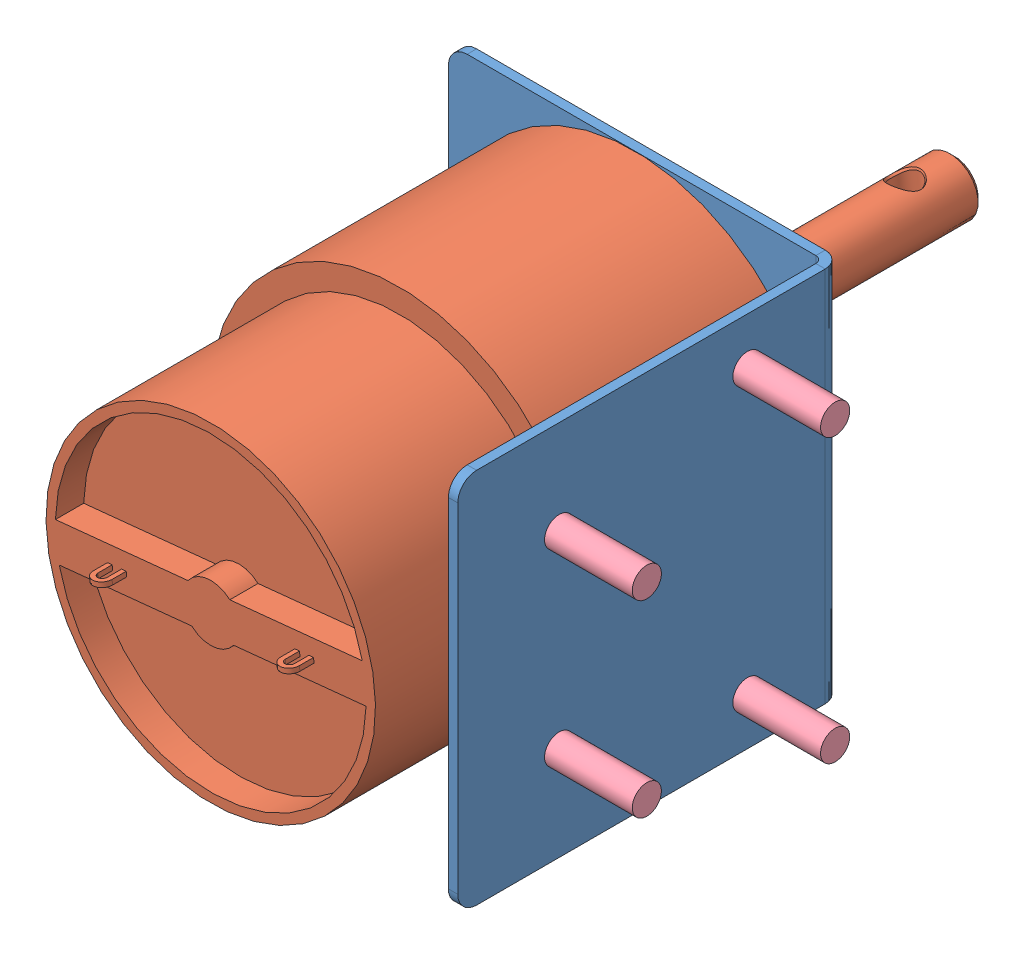
SolidWorks assembly DC motor assembly-12 V , configuration Default. Lengths in mm.
Overall size (52.23 43.84 81.5).
7 component instances, 4 part files, 12 mates.
Components (placement in the parent):
- L-stripe motor holder-1: L-stripe motor holder [Default] at (18.2505 17.963 12.0789) size (40.77 40 40.77)
- Motor for ioe robocon 2018-1: Motor for ioe robocon 2018 [Default] at (-1.9841 17.963 57.0789) x (-0.101002 0.994886 0) z (0 0 -1) size (40 40 81.5)
- Motor-stripe nut-1: Motor-stripe nut [Default] at (-1.9841 17.963 11.0789) x (-0.202187 -0.979347 0) z (0 0 -1) size (20 23.09 5)
- Stripe screw-1: Stripe screw [Default] at (28.3317 32.963 21.0789) x (0 0.680976 -0.732306) z (0 0.732306 0.680976) size (5 10.6 4.9)
- Stripe screw-2: Stripe screw [Default] at (28.3317 2.963 21.0789) x (0 0.97632 -0.216331) z (0 0.216331 0.97632) size (5 10.6 4.9)
- Stripe screw-3: Stripe screw [Default] at (28.3317 7.963 41.0789) x (0 0.554488 -0.832192) z (0 0.832192 0.554488) size (5 10.6 4.9)
- Stripe screw-4: Stripe screw [Default] at (28.3317 27.963 41.0789) x (0 0.554 -0.832517) z (0 0.832517 0.554) size (5 10.6 4.9)
Mates (geometry in assembly coordinates):
- Concentric2: concentric aligned: circle of L-stripe motor holder-1; circle of Motor-stripe nut-1
- Coincident4: coincident anti-aligned: plane of L-stripe motor holder-1 through (18.2505 17.963 11.0789) normal (0 0 -1); plane of Motor-stripe nut-1 through (-1.9841 17.963 11.0789) normal (0 0 1)
- Concentric4: concentric anti-aligned: cylinder of L-stripe motor holder-1 through (19.0159 27.963 41.0789) axis (-1 0 0) radius 1.55; cylinder of Stripe screw-4 through (28.3317 27.963 41.0789) axis (1 0 0) radius 1.55
- Coincident5: coincident: circle of L-stripe motor holder-1; cone of Stripe screw-4 through (18.3317 27.963 41.0789) axis (1 0 0)
- Concentric5: concentric anti-aligned: cylinder of L-stripe motor holder-1 through (19.0159 32.963 21.0789) axis (-1 0 0) radius 1.55; cylinder of Stripe screw-1 through (28.3317 32.963 21.0789) axis (1 0 0) radius 1.55
- Coincident6: coincident: circle of L-stripe motor holder-1; cone of Stripe screw-1 through (18.3317 32.963 21.0789) axis (1 0 0)
- Concentric6: concentric anti-aligned: cylinder of L-stripe motor holder-1 through (19.0159 7.963 41.0789) axis (-1 0 0) radius 1.55; cylinder of Stripe screw-3 through (28.3317 7.963 41.0789) axis (1 0 0) radius 1.55
- Concentric7: concentric anti-aligned: cylinder of L-stripe motor holder-1 through (19.0159 2.963 21.0789) axis (-1 0 0) radius 1.55; cylinder of Stripe screw-2 through (28.3317 2.963 21.0789) axis (1 0 0) radius 1.55
- Coincident7: coincident: circle of L-stripe motor holder-1; cone of Stripe screw-3 through (18.3317 7.963 41.0789) axis (1 0 0)
- Coincident8: coincident: circle of L-stripe motor holder-1; cone of Stripe screw-2 through (18.3317 2.963 21.0789) axis (1 0 0)
- Coincident13: coincident anti-aligned: cylinder of Motor for ioe robocon 2018-1 through (-1.9841 17.963 0.0789) axis (0 0 1) radius 5; circle of Motor-stripe nut-1
- Coincident14: coincident anti-aligned: plane of L-stripe motor holder-1 through (18.2505 17.963 12.0789) normal (0 0 1); plane of Motor for ioe robocon 2018-1 through (-1.9841 17.963 12.0789) normal (0 0 -1)
